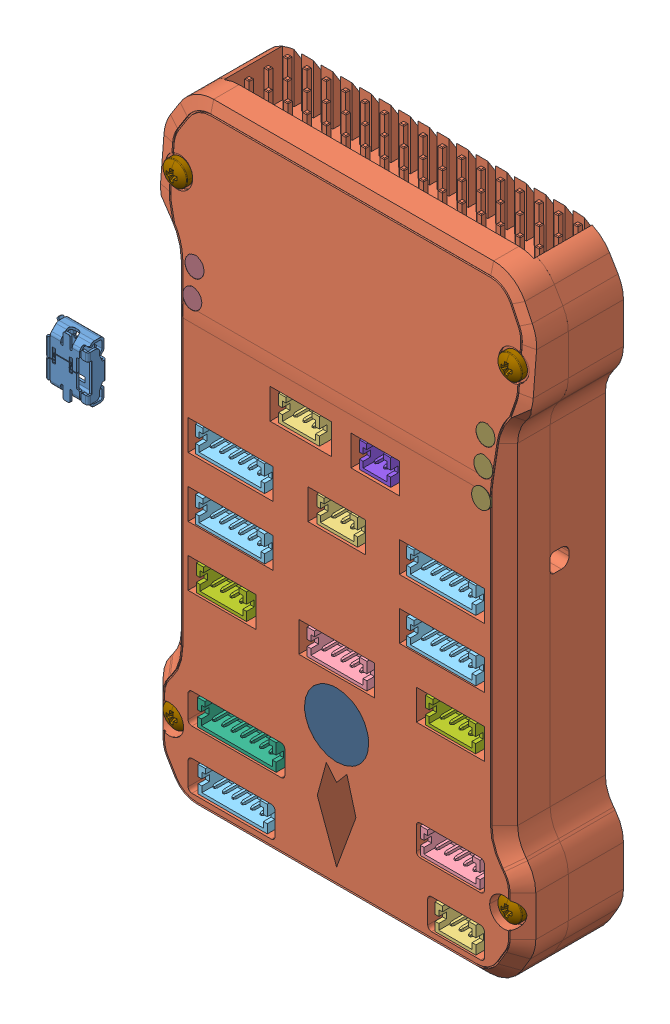
SolidWorks assembly Pixhawk.STEP, configuration Default. Lengths in mm.
Overall size (62.89 81.3 15.33).
24 component instances, 13 part files, 0 mates.
Components (placement in the parent):
- micro USB.STEP-1: micro USB.STEP [Default] at (-38.5288 4.0262 13.8589) x (0 1 0) z (-1 0 0) size (7.98 2.93 5.44)
- Pixhawk APM.STEP-1: Pixhawk APM.STEP [Default] at (-25.3722 -39.1501 0) size (49.31 81.3 15.02)
- DF13-3P-1.25DSA.STEP-1: DF13-3P-1.25DSA.STEP [Default] at (0.001 -60.127 12.2305) x (0 -1 0) z (-1 0 0) size (3.41 6.61 5.41)
- DF13-5P-1.25DSA.STEP-1: DF13-5P-1.25DSA.STEP [Default] at (0.5502 -52.3839 12.2305) x (0 -1 0) z (-1 0 0) size (3.41 6.61 7.91)
- DF13-6P-1.25DSA.STEP-1: DF13-6P-1.25DSA.STEP [Default] at (-27.5951 -60.0382 12.2305) x (0 -1 0) z (-1 0 0) size (3.41 6.61 9.16)
- DF13-7P-1.25DSA.STEP-1: DF13-7P-1.25DSA.STEP [Default] at (-26.4213 -52.4032 12.2305) x (0 -1 0) z (-1 0 0) size (3.41 6.61 10.41)
- DF13-4P-1.25DSA.STEP-1: DF13-4P-1.25DSA.STEP [Default] at (-0.0265 -37.0823 12.2305) x (0 -1 0) z (-1 0 0) size (3.41 6.61 6.66)
- DF13-4P-1.25DSA.STEP-2: DF13-4P-1.25DSA.STEP [Default] at (-30.3382 -37.0823 12.2305) x (0 -1 0) z (-1 0 0) size (3.41 6.61 6.66)
- DF13-5P-1.25DSA.STEP-2: DF13-5P-1.25DSA.STEP [Default] at (-14.4216 -37.0823 12.2305) x (0 -1 0) z (-1 0 0) size (3.41 6.61 7.91)
- DF13-6P-1.25DSA.STEP-2: DF13-6P-1.25DSA.STEP [Default] at (-0.012 -29.2904 12.2305) x (0 -1 0) z (-1 0 0) size (3.41 6.61 9.16)
- DF13-6P-1.25DSA.STEP-3: DF13-6P-1.25DSA.STEP [Default] at (-0.012 -21.2194 12.2305) x (0 -1 0) z (-1 0 0) size (3.41 6.61 9.16)
- DF13-6P-1.25DSA.STEP-4: DF13-6P-1.25DSA.STEP [Default] at (-27.948 -29.2904 12.2305) x (0 -1 0) z (-1 0 0) size (3.41 6.61 9.16)
- DF13-6P-1.25DSA.STEP-5: DF13-6P-1.25DSA.STEP [Default] at (-27.948 -21.2194 12.2305) x (0 -1 0) z (-1 0 0) size (3.41 6.61 9.16)
- DF13-3P-1.25DSA.STEP-2: DF13-3P-1.25DSA.STEP [Default] at (-15.6441 -21.2194 12.2305) x (0 -1 0) z (-1 0 0) size (3.41 6.61 5.41)
- DF13-2P-1.25DSA.STEP-1: DF13-2P-1.25DSA.STEP [Default] at (-11.2684 -12.1811 12.2305) x (0 -1 0) z (-1 0 0) size (3.41 6.61 4.16)
- DF13-3P-1.25DSA.STEP-3: DF13-3P-1.25DSA.STEP [Default] at (-20.7011 -12.1811 12.2305) x (0 -1 0) z (-1 0 0) size (3.41 6.61 5.41)
- pan head cross recess screw_iso_ISO 7045 - M1.6 x 3 - Z --- 3N.STEP-1: pan head cross recess screw_iso_ISO 7045 - M1.6 x 3 - Z --- 3N.STEP [Default] at (21.4278 32.5499 14.8) x (0 0 -1) z (1 0 0) size (4.27 3.2 3.2)
- pan head cross recess screw_iso_ISO 7045 - M1.6 x 3 - Z --- 3N.STEP-2: pan head cross recess screw_iso_ISO 7045 - M1.6 x 3 - Z --- 3N.STEP [Default] at (-22.8722 32.5499 14.8) x (0 0 -1) z (1 0 0) size (4.27 3.2 3.2)
- pan head cross recess screw_iso_ISO 7045 - M1.6 x 3 - Z --- 3N.STEP-3: pan head cross recess screw_iso_ISO 7045 - M1.6 x 3 - Z --- 3N.STEP [Default] at (21.4278 -29.5501 14.8) x (0 0 -1) z (1 0 0) size (4.27 3.2 3.2)
- pan head cross recess screw_iso_ISO 7045 - M1.6 x 3 - Z --- 3N.STEP-4: pan head cross recess screw_iso_ISO 7045 - M1.6 x 3 - Z --- 3N.STEP [Default] at (-22.8722 -29.5501 14.8) x (0 0 -1) z (1 0 0) size (4.27 3.2 3.2)
- Pi_ce10^Pixhawk.STEP-1: Pi_ce10^Pixhawk.STEP [Default] at (-25.3722 -39.1501 14.5) size (8.5 8.5 0.5)
- Pi_ce11^Pixhawk.STEP-1: Pi_ce11^Pixhawk.STEP [Default] at (-25.3722 -39.1501 14.5) size (5.12 11.31 0.5)
- Pi_ce12^Pixhawk.STEP-1: Pi_ce12^Pixhawk.STEP [Default] at (-25.3722 -37.5551 19.1403) x (1 0 0) z (0 0.083045 0.996546) size (2.5 9.53 0.5)
- Pi_ce13^Pixhawk.STEP-1: Pi_ce13^Pixhawk.STEP [Default] at (-25.3722 -37.5551 19.1403) x (1 0 0) z (0 0.083045 0.996546) size (2.5 6.02 0.5)
